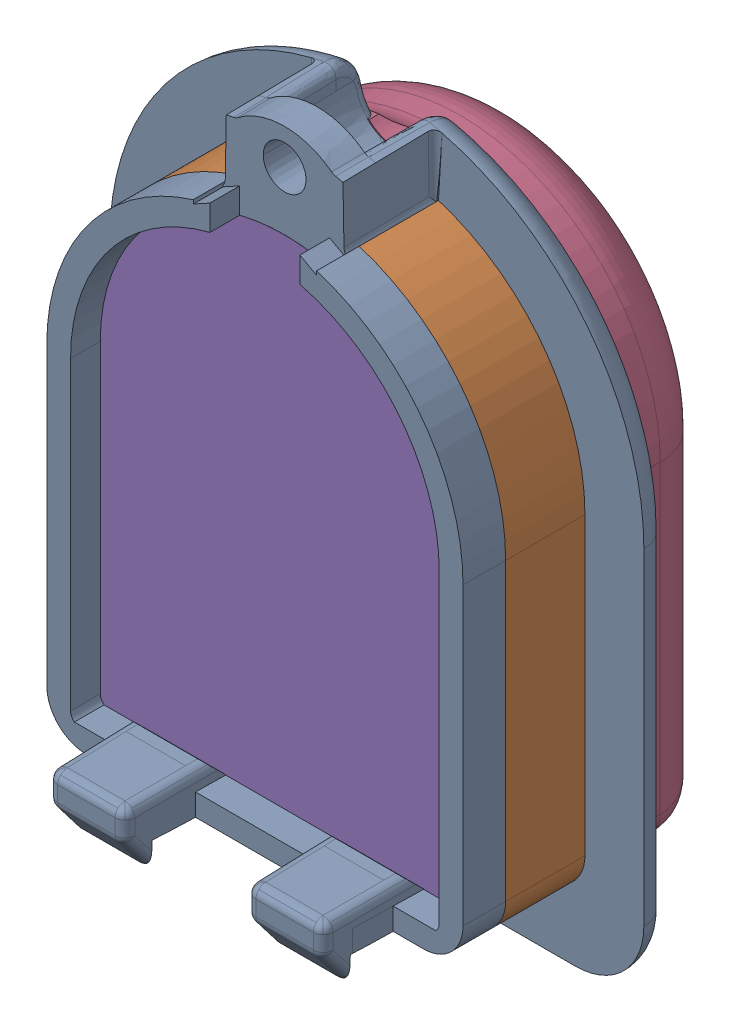
SolidWorks assembly Coord, configuration 默认. Lengths in mm.
Overall size (26.95 34.26 16.66).
6 component instances, 6 part files, 14 mates.
Components (placement in the parent):
- CoordOriginBody-1: CoordOriginBody [默认] at (-2.213 7.3799 -8.324) size (26.95 34.26 11.2)
- CoordTransBody-1: CoordTransBody [默认] at (-2.213 7.3799 -8.324) size (21 26.93 4)
- CoordInsideSKin-1: CoordInsideSKin [默认] at (-2.213 4.0799 -7.824) x (-1 0 0) z (0 0 -1) size (18.6 25.2 5.2)
- CoordoutSkin-1: CoordoutSkin [默认] at (-2.213 4.0799 -7.824) x (-1 0 0) z (0 0 -1) size (21.8 28.5 6)
- CoordLens-1: CoordLens [默认] at (-2.213 7.3799 -7.824) size (18.6 25.2 5.65)
- CoordMarker-1: CoordMarker [默认] at (0.7621 0.6661 -13.024) size (15.6 21.6 1.5)
Mates (geometry in assembly coordinates):
- 重合1: coincident anti-aligned: plane of OriginBody-1 through (-2.213 7.3799 -6.824) normal (0 0 1); plane of TransBody-1 through (7.137 -9.7124 -6.824) normal (0 0 -1)
- 同心1: concentric aligned: cylinder of OriginBody-1 through (-2.213 7.3799 -0.674) axis (0 0 -1) radius 10.5; cylinder of TransBody-1 through (-2.213 7.3799 -0.674) axis (0 0 -1) radius 10.5
- 重合2: coincident aligned: plane of OriginBody-1 through (8.287 7.3799 -0.674) normal (1 0 0); plane of TransBody-1 through (8.287 7.3799 -0.674) normal (1 0 0)
- 重合3: coincident anti-aligned: plane of TransBody-1 through (-2.213 -8.5201 48.523) normal (0 1 0); plane of Lens-1 through (-11.513 -8.5201 -2.174) normal (0 -1 0)
- 同心2: concentric aligned: cylinder of TransBody-1 through (-2.213 7.3799 48.523) axis (0 0 -1) radius 9.3; cylinder of Lens-1 through (-2.213 7.3799 -2.174) axis (0 0 -1) radius 9.3
- 重合5: coincident anti-aligned: plane of CoordInsideSKin-1 through (-11.013 -8.0201 -7.824) normal (0 0 1); plane of Lens-1 through (-2.213 7.3799 -7.824) normal (0 0 -1)
- 重合6: coincident anti-aligned: plane of CoordInsideSKin-1 through (-11.013 -8.0201 -13.024) normal (0 0 -1); plane of outSkin-1 through (-11.013 -8.0201 -13.024) normal (0 0 1)
- 同心4: concentric aligned: cylinder of CoordInsideSKin-1 through (-2.213 7.3799 -13.024) axis (0 0 1) radius 9.3; cylinder of outSkin-1 through (-2.213 7.3799 -13.024) axis (0 0 1) radius 9.3
- 平行2: parallel aligned: plane of CoordInsideSKin-1 through (-11.013 -8.5201 -13.024) normal (0 -1 0); plane of outSkin-1 through (-11.013 -9.3201 -13.024) normal (0 -1 0)
- 重合8: coincident aligned: plane of CoordInsideSKin-1 through (-11.013 -8.0201 -13.024) normal (0 0 -1); plane of CoordMarker-1 through (-9.213 3.7299 -13.024) normal (0 0 -1)
- 宽度1: width aligned: plane of CoordInsideSKin-1 through (7.087 -8.0201 -13.024) normal (1 0 0); plane of CoordMarker-1 through (-11.513 7.3799 -13.024) normal (-1 0 0); plane of CoordInsideSKin-1 through (5.587 -0.2701 -12.274) normal (1 0 0); plane of CoordMarker-1 through (-10.013 1.7299 -12.274) normal (-1 0 0)
- 相切2: tangent: line of CoordInsideSKin-1 through (5.087 -6.5201 -13.024) axis (-1 0 0); cylinder of CoordMarker-1 through (4.787 -6.2701 -11.524) axis (0 0 -1) radius 0.25
- 重合9: coincident anti-aligned: plane of OriginBody-1 through (-11.013 -8.0201 -7.824) normal (0 0 -1); plane of outSkin-1 through (-11.013 -8.0201 -7.824) normal (0 0 1)
- 同心5: concentric aligned: cone of OriginBody-1 through (-2.213 19.6299 -3.824) axis (0 0 1); cylinder of outSkin-1 through (-2.213 19.6299 -17.824) axis (0 0 1) radius 2.0018
